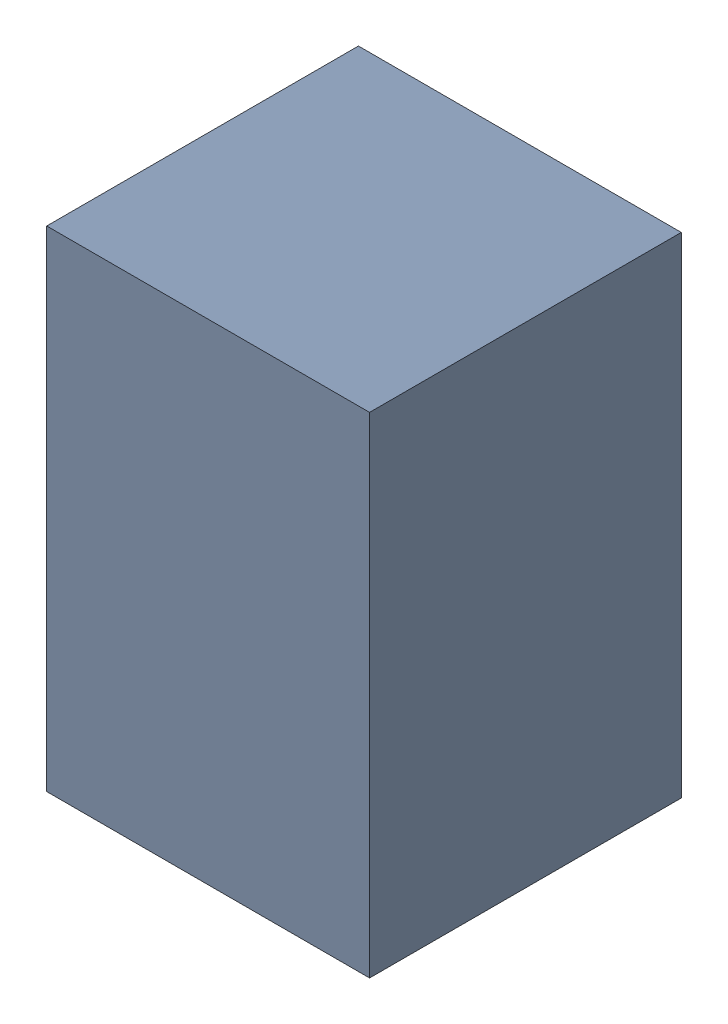
SolidWorks assembly D3, configuration Default. Lengths in mm.
Overall size (1.45 2.2 1.4).
2 component instances, 1 part files, 0 mates.
Components (placement in the parent):
- 959209888-1: 959209888 [Default] at (108.585 90.769 0) size (1.45 2.2 1.4)
  - Extruded-29-1: Extruded-29 [Default] at origin size (1.45 2.2 1.4)
